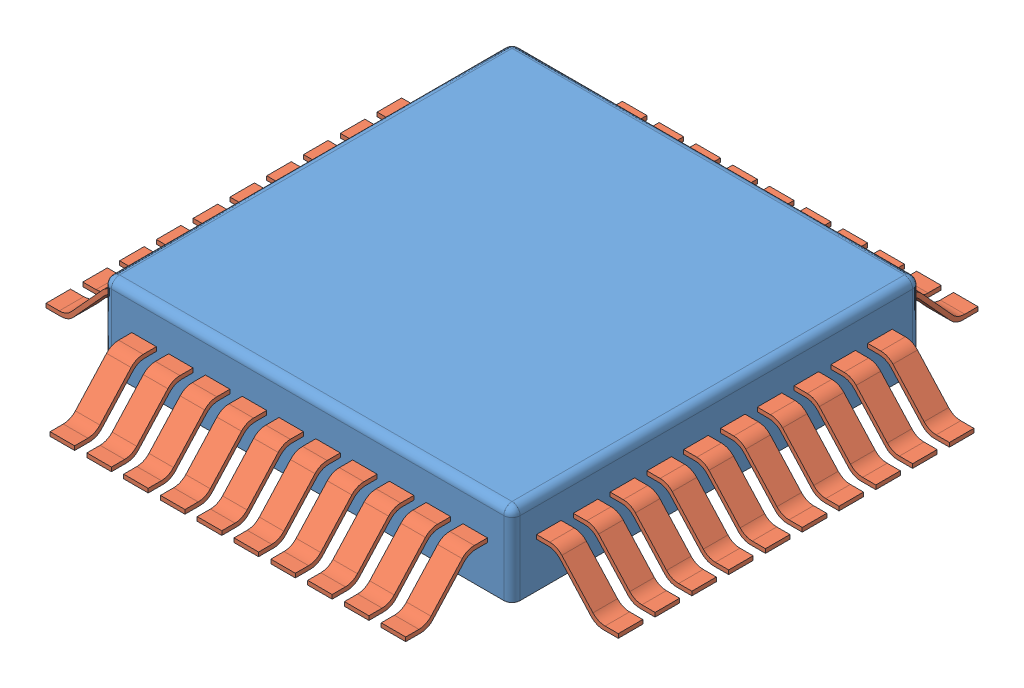
SolidWorks assembly 3652, configuration Default. Lengths in mm.
Overall size (7 1.04 7).
41 component instances, 2 part files, 6 mates.
Components (placement in the parent):
- 333-1: 333 [Default] at (-0.2652 1.6373 6.4642) size (5 1 5)
- 00.2-1: 00.2 [Default] at (4.7348 2.2373 1.9642) size (1 0.6 0.3)
- 00.2-2: 00.2 [Default] at (4.7348 2.2373 2.4142) size (1 0.6 0.3)
- 00.2-3: 00.2 [Default] at (4.7348 2.2373 2.8642) size (1 0.6 0.3)
- 00.2-4: 00.2 [Default] at (4.7348 2.2373 3.3142) size (1 0.6 0.3)
- 00.2-5: 00.2 [Default] at (4.7348 2.2373 3.7642) size (1 0.6 0.3)
- 00.2-6: 00.2 [Default] at (4.7348 2.2373 4.2142) size (1 0.6 0.3)
- 00.2-7: 00.2 [Default] at (4.7348 2.2373 4.6642) size (1 0.6 0.3)
- 00.2-8: 00.2 [Default] at (4.7348 2.2373 5.1142) size (1 0.6 0.3)
- 00.2-9: 00.2 [Default] at (4.7348 2.2373 5.5642) size (1 0.6 0.3)
- 00.2-10: 00.2 [Default] at (4.7348 2.2373 6.0142) size (1 0.6 0.3)
- 00.2-11: 00.2 [Default] at (-0.2652 2.2373 2.4142) x (-1 0 0) z (0 0 -1) size (1 0.6 0.3)
- 00.2-12: 00.2 [Default] at (-0.2652 2.2373 2.8642) x (-1 0 0) z (0 0 -1) size (1 0.6 0.3)
- 00.2-13: 00.2 [Default] at (-0.2652 2.2373 3.3142) x (-1 0 0) z (0 0 -1) size (1 0.6 0.3)
- 00.2-14: 00.2 [Default] at (-0.2652 2.2373 3.7642) x (-1 0 0) z (0 0 -1) size (1 0.6 0.3)
- 00.2-15: 00.2 [Default] at (-0.2652 2.2373 4.2142) x (-1 0 0) z (0 0 -1) size (1 0.6 0.3)
- 00.2-16: 00.2 [Default] at (-0.2652 2.2373 4.6642) x (-1 0 0) z (0 0 -1) size (1 0.6 0.3)
- 00.2-17: 00.2 [Default] at (-0.2652 2.2373 5.1142) x (-1 0 0) z (0 0 -1) size (1 0.6 0.3)
- 00.2-18: 00.2 [Default] at (-0.2652 2.2373 5.5642) x (-1 0 0) z (0 0 -1) size (1 0.6 0.3)
- 00.2-19: 00.2 [Default] at (-0.2652 2.2373 6.0142) x (-1 0 0) z (0 0 -1) size (1 0.6 0.3)
- 00.2-20: 00.2 [Default] at (0.2348 2.2019 6.4642) x (0 0 1) z (-1 0 0) size (1 0.6 0.3)
- 00.2-21: 00.2 [Default] at (-0.2652 2.2373 1.9642) x (-1 0 0) z (0 0 -1) size (1 0.6 0.3)
- 00.2-22: 00.2 [Default] at (0.6848 2.2019 6.4642) x (0 0 1) z (-1 0 0) size (1 0.6 0.3)
- 00.2-23: 00.2 [Default] at (1.1348 2.2019 6.4642) x (0 0 1) z (-1 0 0) size (1 0.6 0.3)
- 00.2-24: 00.2 [Default] at (1.5848 2.2019 6.4642) x (0 0 1) z (-1 0 0) size (1 0.6 0.3)
- 00.2-25: 00.2 [Default] at (2.0348 2.2019 6.4642) x (0 0 1) z (-1 0 0) size (1 0.6 0.3)
- 00.2-26: 00.2 [Default] at (2.4848 2.2019 6.4642) x (0 0 1) z (-1 0 0) size (1 0.6 0.3)
- 00.2-27: 00.2 [Default] at (2.9348 2.2019 6.4642) x (0 0 1) z (-1 0 0) size (1 0.6 0.3)
- 00.2-28: 00.2 [Default] at (3.3848 2.2019 6.4642) x (0 0 1) z (-1 0 0) size (1 0.6 0.3)
- 00.2-29: 00.2 [Default] at (3.8348 2.2019 6.4642) x (0 0 1) z (-1 0 0) size (1 0.6 0.3)
- 00.2-30: 00.2 [Default] at (4.2848 2.2019 6.4642) x (0 0 1) z (-1 0 0) size (1 0.6 0.3)
- 00.2-31: 00.2 [Default] at (0.6848 2.2019 1.4642) x (0 0 -1) z (1 0 0) size (1 0.6 0.3)
- 00.2-32: 00.2 [Default] at (1.1348 2.2019 1.4642) x (0 0 -1) z (1 0 0) size (1 0.6 0.3)
- 00.2-33: 00.2 [Default] at (1.5848 2.2019 1.4642) x (0 0 -1) z (1 0 0) size (1 0.6 0.3)
- 00.2-34: 00.2 [Default] at (2.0348 2.2019 1.4642) x (0 0 -1) z (1 0 0) size (1 0.6 0.3)
- 00.2-35: 00.2 [Default] at (2.4848 2.2019 1.4642) x (0 0 -1) z (1 0 0) size (1 0.6 0.3)
- 00.2-36: 00.2 [Default] at (2.9348 2.2019 1.4642) x (0 0 -1) z (1 0 0) size (1 0.6 0.3)
- 00.2-37: 00.2 [Default] at (3.3848 2.2019 1.4642) x (0 0 -1) z (1 0 0) size (1 0.6 0.3)
- 00.2-38: 00.2 [Default] at (3.8348 2.2019 1.4642) x (0 0 -1) z (1 0 0) size (1 0.6 0.3)
- 00.2-39: 00.2 [Default] at (4.2848 2.2019 1.4642) x (0 0 -1) z (1 0 0) size (1 0.6 0.3)
- 00.2-40: 00.2 [Default] at (0.2348 2.2019 1.4642) x (0 0 -1) z (1 0 0) size (1 0.6 0.3)
Mates (geometry in assembly coordinates):
- Coincident1: coincident anti-aligned: plane of 333-1 through (4.7348 2.6373 6.4642) normal (1 0 0); plane of 00.2-1 through (4.7348 2.1873 2.1142) normal (-1 0 0)
- Distance2: distance = 0.25 mm: line of 00.2-1 through (4.7348 2.2373 1.8142) axis (0 -1 0); line of 333-1 through (4.7348 1.6373 1.5642) axis (0 1 0)
- Distance3: distance = 0.3 mm: line of 00.2-1 through (4.7348 2.2373 2.1142) axis (0 0 -1); line of 333-1 through (4.7348 2.5373 1.5642) axis (0 0 1)
- Coincident10: coincident anti-aligned: plane of 333-1 through (-0.2652 2.6373 6.4642) normal (0 0 1); plane of 00.2-20 through (0.0848 2.1519 6.4642) normal (0 0 -1)
- Distance11: distance = 0.25 mm: line of 00.2-20 through (0.0848 2.2019 6.4642) axis (0 -1 0); line of 333-1 through (-0.1652 2.5373 6.4642) axis (0 -1 0)
- Distance12: distance = 0.25 mm: line of 00.2-20 through (0.0848 2.2019 6.4642) axis (1 0 0); cylinder of 333-1 through (-0.2652 2.5373 6.3642) axis (1 0 0) radius 0.1
